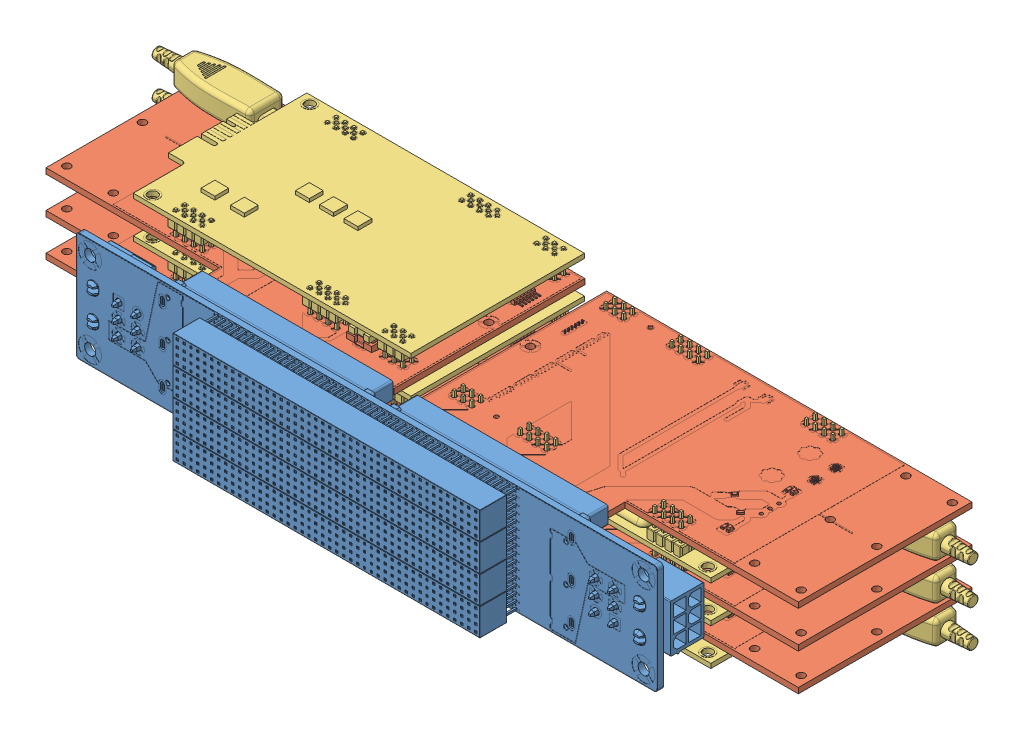
SolidWorks assembly 6xCardAdapters, configuration Default. Lengths in mm.
Overall size (235.24 37.46 77.59).
19 component instances, 3 part files, 6 mates.
Components (placement in the parent):
- HYDRA_VMM3_Adapter-1: HYDRA_VMM3_Adapter [Default] at (-95.7446 58.0353 -1.1459) size (170.7 31.9 24.82)
- 1xCardAdapter-1: 1xCardAdapter [Default] at (-82.6422 -78.7434 19.2411) x (1 0 0) z (0 1 0) size (114.47 61 10.4)
  - HYDRA_VMM3_CARD-1: HYDRA_VMM3_CARD [Default] at (37.8026 54.1071 80.2687) size (105.25 61 6.02)
  - VMM3Hybrid_Reworked-1: VMM3Hybrid_Reworked [Default] at (90.3748 34.5693 88.1363) x (-1 0 0) z (0 0 -1) size (114.42 50 10.4)
- 1xCardAdapter-2: 1xCardAdapter [Default] at (-82.6422 -89.4034 19.2411) x (1 0 0) z (0 1 0) size (114.47 61 10.4)
  - HYDRA_VMM3_CARD-1: HYDRA_VMM3_CARD [Default] at (37.8026 54.1071 80.2687) size (105.25 61 6.02)
  - VMM3Hybrid_Reworked-1: VMM3Hybrid_Reworked [Default] at (90.3748 34.5693 88.1363) x (-1 0 0) z (0 0 -1) size (114.42 50 10.4)
- 1xCardAdapter-3: 1xCardAdapter [Default] at (-82.6422 -100.0634 19.2411) x (1 0 0) z (0 1 0) size (114.47 61 10.4)
  - HYDRA_VMM3_CARD-1: HYDRA_VMM3_CARD [Default] at (37.8026 54.1071 80.2687) size (105.25 61 6.02)
  - VMM3Hybrid_Reworked-1: VMM3Hybrid_Reworked [Default] at (90.3748 34.5693 88.1363) x (-1 0 0) z (0 0 -1) size (114.42 50 10.4)
- 1xCardAdapter-4: 1xCardAdapter [Default] at (104.5031 83.394 19.2411) x (-1 0 0) z (0 -1 0) size (114.47 61 10.4)
  - HYDRA_VMM3_CARD-1: HYDRA_VMM3_CARD [Default] at (37.8026 54.1071 80.2687) size (105.25 61 6.02)
  - VMM3Hybrid_Reworked-1: VMM3Hybrid_Reworked [Default] at (90.3748 34.5693 88.1363) x (-1 0 0) z (0 0 -1) size (114.42 50 10.4)
- 1xCardAdapter-5: 1xCardAdapter [Default] at (104.5031 72.734 19.2411) x (-1 0 0) z (0 -1 0) size (114.47 61 10.4)
  - HYDRA_VMM3_CARD-1: HYDRA_VMM3_CARD [Default] at (37.8026 54.1071 80.2687) size (105.25 61 6.02)
  - VMM3Hybrid_Reworked-1: VMM3Hybrid_Reworked [Default] at (90.3748 34.5693 88.1363) x (-1 0 0) z (0 0 -1) size (114.42 50 10.4)
- 1xCardAdapter-6: 1xCardAdapter [Default] at (104.5031 62.074 19.2411) x (-1 0 0) z (0 -1 0) size (114.47 61 10.4)
  - HYDRA_VMM3_CARD-1: HYDRA_VMM3_CARD [Default] at (37.8026 54.1071 80.2687) size (105.25 61 6.02)
  - VMM3Hybrid_Reworked-1: VMM3Hybrid_Reworked [Default] at (90.3748 34.5693 88.1363) x (-1 0 0) z (0 0 -1) size (114.42 50 10.4)
Mates (geometry in assembly coordinates):
- Coincident1: coincident anti-aligned: plane of HYDRA_VMM3_Adapter-1 through (-20.4371 1.5253 -6.9559) normal (0 1 0); plane of 1xCardAdapter-1/HYDRA_VMM3_CARD-1 through (-44.8396 1.5253 -34.8659) normal (0 -1 0)
- Coincident2: coincident anti-aligned: plane of HYDRA_VMM3_Adapter-1 through (-3.6146 2.4253 -4.3659) normal (0 0 -1); plane of 1xCardAdapter-1/HYDRA_VMM3_CARD-1 through (5.0354 1.5253 -4.3659) normal (0 0 1)
- Coincident3: coincident anti-aligned: plane of HYDRA_VMM3_Adapter-1 through (5.7854 2.4253 -6.9559) normal (-1 0 0); plane of 1xCardAdapter-1/HYDRA_VMM3_CARD-1 through (5.7854 1.5253 -9.6159) normal (1 0 0)
- Coincident5: coincident anti-aligned: plane of HYDRA_VMM3_Adapter-1 through (42.2979 1.5253 -6.9559) normal (0 1 0); plane of 1xCardAdapter-4/HYDRA_VMM3_CARD-1 through (66.7004 1.5253 -34.8659) normal (0 -1 0)
- Coincident6: coincident anti-aligned: plane of HYDRA_VMM3_Adapter-1 through (25.4754 2.4253 -4.3659) normal (0 0 -1); plane of 1xCardAdapter-4/HYDRA_VMM3_CARD-1 through (16.8254 3.1253 -4.3659) normal (0 0 1)
- Coincident7: coincident anti-aligned: plane of HYDRA_VMM3_Adapter-1 through (16.0754 2.4253 -6.9559) normal (1 0 0); plane of 1xCardAdapter-4/HYDRA_VMM3_CARD-1 through (16.0754 3.1253 -9.6159) normal (-1 0 0)
